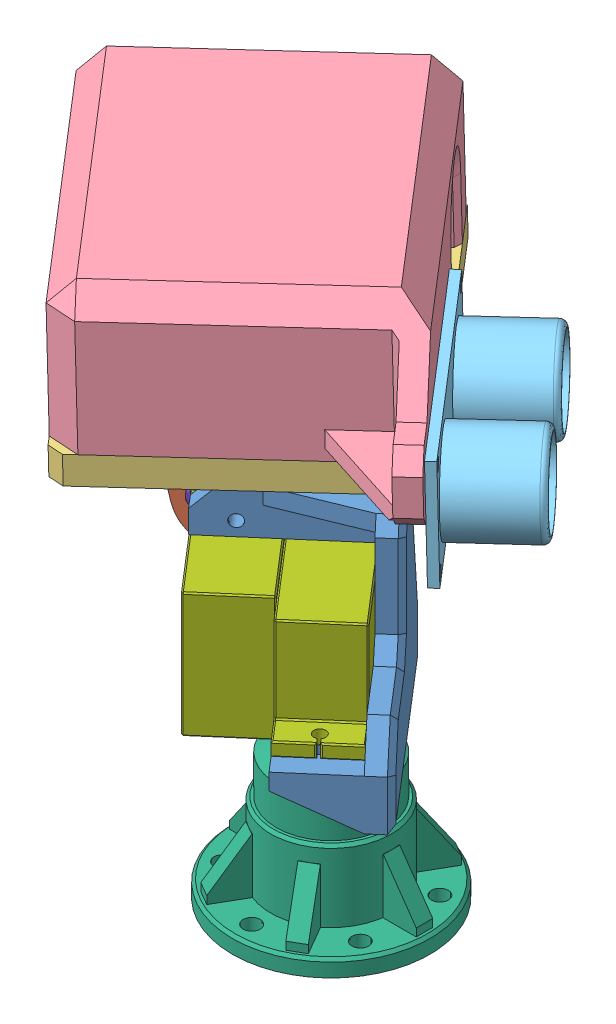
SolidWorks assembly headSub, configuration Default. Lengths in mm.
Overall size (98.27 110.63 90.98).
9 component instances, 8 part files, 23 mates.
Components (placement in the parent):
- headServoMount-1: headServoMount [Default] at (-11 24.2018 4.7087) x (0.652454 0 0.757829) z (0.757829 0 -0.652454) size (39.75 36.12 28.6)
- headMount-1: headMount [Default] at (-29.2346 24.4603 3.4607) x (0.014946 -0.999805 -0.012868) z (-0.652454 0 -0.757829) size (40 30 34)
- headBaseplate-1: headBaseplate [Default] at (-62.223 48.3561 8.11) x (0.652454 0 0.757829) z (-0.757681 -0.019722 0.652327) size (60 5 50)
- headCanopy-1: headCanopy [Default] at (-24.7873 79.3364 -24.1203) x (0.652454 0 0.757829) z (0.014946 -0.999805 -0.012868) size (76.5 50 25)
- usSensor-2: usSensor [Default] at (23.6912 44.3432 31.1298) x (-0.652454 0 -0.757829) z (0.014946 -0.999805 -0.012868) size (43 15.6 26)
- mastMount-top-1: mastMount-top [Default] at (-11.9091 -31.2972 13.0788) size (36 28 36)
- sg90Servo-1: sg90Servo [Default] at (-11 24.0708 4.7087) x (0.652454 0 0.757829) z (0.757829 0 -0.652454) size (32.7 29.37 12.3)
- sg90Servo-2: sg90Servo [Default] at (-8.4956 24.5458 26.4696) x (0 -1 0) z (0.757829 0 -0.652454) size (32.7 29.37 12.3)
- sg90ServoHorn-star-1: sg90ServoHorn-star [Default] at (-35.5492 20.6393 8.8973) x (0.014946 -0.999805 -0.012868) z (-0.757681 -0.019722 0.652327) size (34.4 4 15.7)
Mates (geometry in assembly coordinates):
- Parallel8: parallel aligned: plane of headMount-1 through (-31.8444 24.4603 0.4294) normal (-0.652454 0 -0.757829); plane of headBaseplate-1 through (-62.2977 53.3551 8.1744) normal (-0.652454 0 -0.757829)
- Coincident41: coincident anti-aligned: plane of headMount-1 through (-32.2098 48.8996 0.7439) normal (-0.014946 0.999805 0.012868); plane of headBaseplate-1 through (-62.223 48.3561 8.11) normal (0.014946 -0.999805 -0.012868)
- Coincident45: coincident anti-aligned: plane of headBaseplate-1 through (-62.2977 53.3551 8.1744) normal (-0.014946 0.999805 0.012868); plane of headCanopy-1 through (-24.4136 54.3412 -24.442) normal (0.014946 -0.999805 -0.012868)
- Distance10: distance = 12 mm aligned: plane of headMount-1 through (-9.661 24.4603 26.1956) normal (0.652454 0 0.757829); plane of headBaseplate-1 through (-23.1505 53.3551 53.6441) normal (0.652454 0 0.757829)
- Distance11: distance = 13 mm aligned: plane of headBaseplate-1 through (-24.4136 54.3412 -24.442) normal (0.757681 0.019722 -0.652327); plane of headMount-1 through (-24.6891 24.6466 -5.731) normal (0.757681 0.019722 -0.652327)
- Concentric3: concentric anti-aligned: cylinder of headBaseplate-1 through (-24.8573 52.2529 -18.122) axis (-0.014946 0.999805 0.012868) radius 1.55; cylinder of headCanopy-1 through (-24.9171 56.2521 -18.0705) axis (0.014946 -0.999805 -0.012868) radius 1.55
- Concentric4: concentric anti-aligned: cylinder of headBaseplate-1 through (-22.6471 51.4443 47.2726) axis (-0.014946 0.999805 0.012868) radius 1.55; cylinder of headCanopy-1 through (-22.7069 55.4435 47.3241) axis (0.014946 -0.999805 -0.012868) radius 1.55
- Coincident63: coincident anti-aligned: plane of headCanopy-1 through (14.4347 74.3374 21.2851) normal (0.757681 0.019722 -0.652327); plane of usSensor-2 through (23.6912 44.3432 31.1298) normal (-0.757681 -0.019722 0.652327)
- Distance17: distance = 15 mm aligned: plane of usSensor-2 through (24.6045 64.3709 30.3434) normal (-0.014946 0.999805 0.012868); plane of headCanopy-1 through (-24.7873 79.3364 -24.1203) normal (-0.014946 0.999805 0.012868)
- Distance18: distance = 4 mm aligned: plane of usSensor-2 through (-3.1521 44.3747 -2.5006) normal (-0.652454 0 -0.757829); plane of headCanopy-1 through (-45.3821 78.3502 28.5792) normal (-0.652454 0 -0.757829)
- Coincident66: coincident anti-aligned: plane of headServoMount-1 through (-11 24.2018 4.7087) normal (-0.757829 0 0.652454); plane of sg90Servo-1 through (-11 1.8458 4.7087) normal (0.757829 0 -0.652454)
- Coincident67: coincident anti-aligned: plane of sg90Servo-1 through (-20.3213 1.8458 12.7339) normal (-0.757829 0 0.652454); plane of sg90Servo-2 through (-22.9964 24.5458 9.6268) normal (0.757829 0 -0.652454)
- Coincident68: coincident aligned: plane of sg90Servo-1 through (-11 1.8458 4.7087) normal (-0.652454 0 -0.757829); plane of sg90Servo-2 through (-20.3213 -3.1542 12.7339) normal (-0.652454 0 -0.757829)
- Coincident69: coincident aligned: plane of sg90Servo-1 through (-11 1.8458 4.7087) normal (0 -1 0); plane of sg90Servo-2 through (-22.9964 1.8458 9.6268) normal (0 -1 0)
- Concentric8: concentric anti-aligned: cylinder of headServoMount-1 through (0.9769 -3.1552 28.046) axis (0 1 0) radius 1.1; cylinder of sg90Servo-1 through (0.9769 24.0719 28.046) axis (0 -1 0) radius 1.1
- Coincident71: coincident anti-aligned: plane of headServoMount-1 through (-27.0007 5.9458 18.4845) normal (0 1 0); plane of sg90Servo-1 through (7.0729 5.9458 25.7006) normal (0 -1 0)
- Concentric9: concentric aligned: cylinder of mastMount-top-1 through (-11.9091 -5.2972 13.0788) axis (0 1 0) radius 2.4; cylinder of sg90Servo-1 through (-11.9091 -5.2972 13.0788) axis (0 1 0) radius 1.984
- Coincident72: coincident anti-aligned: plane of mastMount-top-1 through (-11.9091 -5.2972 13.0788) normal (0 1 0); plane of sg90Servo-1 through (-11.9091 -5.2972 13.0788) normal (0 -1 0)
- Coincident73: coincident anti-aligned: plane of headMount-1 through (-29.2346 24.4603 3.4607) normal (0.652454 0 0.757829); plane of sg90ServoHorn-star-1 through (-35.5492 20.6393 8.8973) normal (-0.652454 0 -0.757829)
- Parallel9: parallel anti-aligned: plane of headMount-1 through (-25.5566 45.4947 39.8809) normal (0.014946 -0.999805 -0.012868); plane of sg90ServoHorn-star-1 through (-34.5966 20.6393 10.0037) normal (-0.014946 0.999805 0.012868)
- Concentric12: concentric aligned: cylinder of headMount-1 through (-35.9719 18.7958 3.9816) axis (0.652454 0 0.757829) radius 2.4; cylinder of sg90ServoHorn-star-1 through (-33.3621 18.7958 7.013) axis (0.652454 0 0.757829) radius 1.2
- Concentric13: concentric aligned: cylinder of sg90Servo-2 through (-32.3175 18.7958 8.2262) axis (0.652454 0 0.757829) radius 1.984; cylinder of sg90ServoHorn-star-1 through (-32.3175 18.7958 8.2262) axis (0.652454 0 0.757829) radius 2.4
- Coincident78: coincident anti-aligned: plane of sg90Servo-2 through (-32.3175 18.7958 8.2262) normal (-0.652454 0 -0.757829); plane of sg90ServoHorn-star-1 through (-32.3175 18.7958 8.2262) normal (0.652454 0 0.757829)
